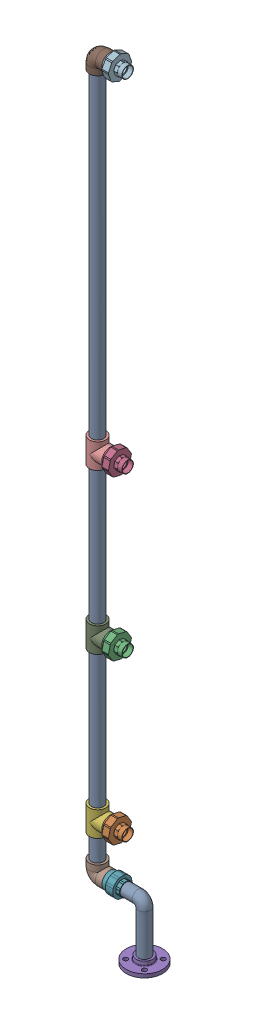
SolidWorks assembly DN40 Stainless-Steel Water Distributor Assembly, configuration Default. Lengths in mm.
Overall size (334.07 3215.43 212.13).
12 component instances, 6 part files, 16 mates.
Components (placement in the parent):
- DN50 PPR water distribution pipe-1: DN50 PPR water distribution pipe [Default] at origin size (244 3175 50)
- DN50 PPR male-thread union-2: DN50 PPR male-thread union [Default] at (-110.1859 414 0) x (1 0 0) z (0 0.815822 -0.578303) size (73 95.5 95.5)
- DN50 PPR male-thread union-3: DN50 PPR male-thread union [Default] at (-110.1859 1074 0) x (1 0 0) z (0 0.815822 -0.578303) size (73 95.5 95.5)
- DN50 PPR male-thread union-4: DN50 PPR male-thread union [Default] at (-110.1859 1734 0) x (1 0 0) z (0 0.815822 -0.578303) size (73 95.5 95.5)
- DN40-PN25 threaded flange-1: DN40-PN25 threaded flange [Default] at (0 -15 0) x (0 1 0) z (0.707107 0 0.707107) size (34 150 150)
- DN50 PPR tee-1: DN50 PPR tee [Default] at (-194 414 0) size (85.5 103 68)
- DN50 PPR female-thread straight connector-1: DN50 PPR female-thread straight connector [Default] at (-142.5 216 0) x (1 0 0) z (0 0.920901 -0.389797) size (67 79.98 79.98)
- DN50 PPR elbow-1: DN50 PPR elbow [Default] at (-169 241 0) size (85.5 85.5 68)
- DN50 PPR tee-2: DN50 PPR tee [Default] at (-194 1074 0) size (85.5 103 68)
- DN50 PPR tee-3: DN50 PPR tee [Default] at (-194 1734 0) size (85.5 103 68)
- DN50 PPR elbow-2: DN50 PPR elbow [Default] at (-169 3125 0) x (1 0 0) z (0 0 -1) size (85.5 85.5 68)
- DN50 PPR male-thread union-5: DN50 PPR male-thread union [Default] at (-110.1859 3150 0) x (1 0 0) z (0 0.057891 0.998323) size (73 95.5 95.5)
Mates (geometry in assembly coordinates):
- Coincident3: coordinate: point of ong chia nuoc DN50 PPR-1
- Concentric3: concentric anti-aligned: cylinder of ong chia nuoc DN50 PPR-1 through (0 190 0) axis (0 -1 0) radius 25; cylinder of Mat bich DN40-PN25 ren-3b-1 through (0 19 0) axis (0 1 0) radius 23.4105
- Angle1: planar angle = 0.785398 rad aligned: plane of Mat bich DN40-PN25 ren-3b-1 through (0 -15 0) normal (0.707107 0 0.707107); plane of assembly through (0 0 0) normal (1 0 0)
- Distance2: distance = 15 mm aligned: plane of Mat bich DN40-PN25 ren-3b-1 through (0 -15 0) normal (0 -1 0); plane of ong chia nuoc DN50 PPR-1 through (0 0 0) normal (0 -1 0)
- Concentric5: concentric aligned: cylinder of ong chia nuoc DN50 PPR-1 through (-194 3124 0) axis (0 -1 0) radius 25; cylinder of tee DN50 PPR-1 through (-194 465.5 0) axis (0 -1 0) radius 34
- Concentric6: concentric anti-aligned: cylinder of ong chia nuoc DN50 PPR-1 through (-118.15 414 0) axis (-1 0 0) radius 24.15; cylinder of tee DN50 PPR-1 through (-228.001 414 0) axis (1 0 0) radius 25
- Concentric7: concentric anti-aligned: cone of ong chia nuoc DN50 PPR-1 through (-148.15 414 0) axis (1 0 0); cylinder of Zac co ren ngoai DN50 PPR-2 through (-110.1859 414 0) axis (-1 0 0) radius 34
- Coincident12: coincident anti-aligned: plane of Zac co ren ngoai DN50 PPR-2 through (-142.5 433.6623 27.7379) normal (-1 0 0); plane of tee DN50 PPR-1 through (-142.5 414 0) normal (1 0 0)
- Concentric9: concentric anti-aligned: cylinder of noi thang ren trong DN50 PPR-1 through (-142.5 216 0) axis (-1 0 0) radius 24.15; cylinder of ong chia nuoc DN50 PPR-1 through (-168 216 0) axis (1 0 0) radius 25
- Concentric10: concentric aligned: cylinder of co DN50 PPR-1 through (-194 267.5 0) axis (0 -1 0) radius 25; cylinder of ong chia nuoc DN50 PPR-1 through (-194 3124 0) axis (0 -1 0) radius 25
- Concentric11: concentric aligned: cylinder of ong chia nuoc DN50 PPR-1 through (-168 216 0) axis (1 0 0) radius 25; cylinder of co DN50 PPR-1 through (-169 216 0) axis (1 0 0) radius 25
- Coincident15: coincident anti-aligned: plane of noi thang ren trong DN50 PPR-1 through (-142.5 229.2531 31.3106) normal (-1 0 0); plane of co DN50 PPR-1 through (-142.5 216 0) normal (1 0 0)
- Concentric12: concentric anti-aligned: cylinder of ong chia nuoc DN50 PPR-1 through (-194 3124 0) axis (0 -1 0) radius 25; cylinder of co DN50 PPR-2 through (-194 3098.5 0) axis (0 1 0) radius 34
- Concentric13: concentric anti-aligned: cylinder of ong chia nuoc DN50 PPR-1 through (-111.85 3150 0) axis (-1 0 0) radius 25; cylinder of co DN50 PPR-2 through (-169 3150 0) axis (1 0 0) radius 34
- Concentric14: concentric: cylinder of co DN50 PPR-2 through (-169 3150 0) axis (1 0 0) radius 34; cylinder of Zac co ren ngoai DN50 PPR-5 through (-110.1859 3150 0) axis (-1 0 0) radius 25
- Coincident16: coincident anti-aligned: plane of co DN50 PPR-2 through (-142.5 3150 0) normal (1 0 0); plane of Zac co ren ngoai DN50 PPR-5 through (-142.5 3116.057 1.9683) normal (-1 0 0)
